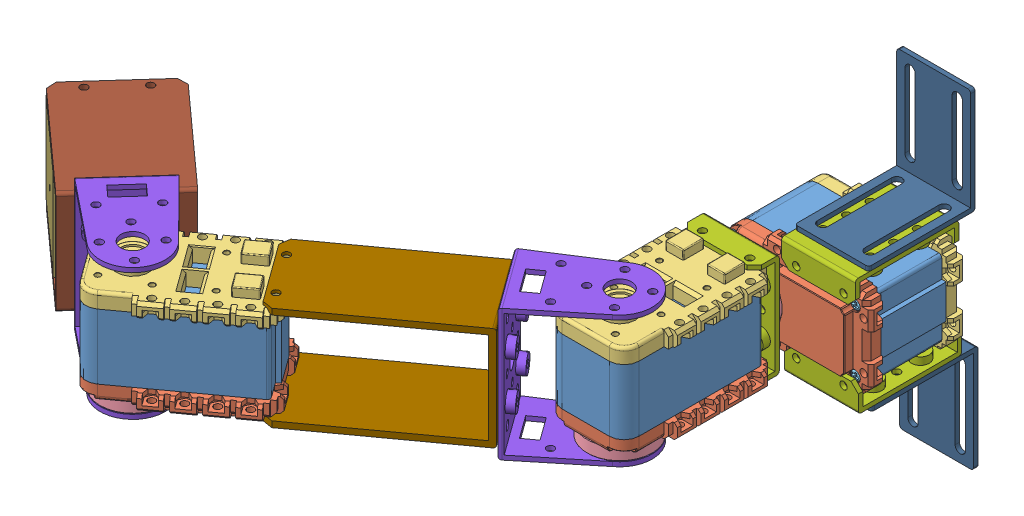
SolidWorks assembly AX-12A, configuration Default. Lengths in mm.
Overall size (199.49 111 175.01).
27 component instances, 12 part files, 97 mates.
Components (placement in the parent):
- AX-12A-01-1: AX-12A-01 [Default] at origin size (48.5 26 22)
- AX-12A-02-1: AX-12A-02 [Default] at (0 0 13.5) size (50 32 8)
- AX-12A-03-1: AX-12A-03 [Default] at (0 0 -13.5) x (1 0 0) z (0 0 -1) size (50 32 8)
- AX-12A-04-1: AX-12A-04 [Default] at (0 0 21) size (22 22 6.7)
- SetScrew-5: SetScrew [Default] at (33 10.4 14.5) x (0.31498 0.949098 0) z (0 0 -1) size (3.3 3.3 29.44)
- SetScrew-6: SetScrew [Default] at (-9 9.25 14.5) x (0.31498 0.949098 0) z (0 0 -1) size (3.3 3.3 29.44)
- SetScrew-7: SetScrew [Default] at (-9 -9.25 14.5) x (-0.839745 -0.542981 0) z (0 0 -1) size (3.3 3.3 29.44)
- SetScrew-8: SetScrew [Default] at (33 -10.4 14.5) x (0.31498 0.949098 0) z (0 0 -1) size (3.3 3.3 29.44)
- pan head cross recess screw_iso-1: pan head cross recess screw_iso [ISO 7045 - M2.5 x 8 - Z --- 8C] at (0 0 21.6) x (0 0 -1) z (0.97903 -0.203716 0) size (10.05 5 5)
- servovas-1: servovas [Default] at (34.75 19.5 -17.5) x (0 0 1) z (0 -1 0) size (35 25 8.5)
- servovas-2: servovas [Default] at (10.75 -19.5 -17.5) x (0 0 1) z (0 1 0) size (35 25 8.5)
- AX-12A-01-2: AX-12A-01 [Default] at (0.5 0 63) x (0 0 -1) z (0 -1 0) size (48.5 26 22)
- AX-12A-02-2: AX-12A-02 [Default] at (0.5 -13.5 63) x (0 0 -1) z (0 -1 0) size (50 32 8)
- AX-12A-03-2: AX-12A-03 [Default] at (0.5 13.5 63) x (0 0 -1) z (0 1 0) size (50 32 8)
- AX-12A-04-2: AX-12A-04 [Default] at (0.5 -20.45 63) x (0.809362 0 -0.587311) z (0 -1 0) size (22 22 6.7)
- servovas-3: servovas [Default] at (12.5 -17.5 21) x (0 1 0) z (0 0 1) size (35 25 8.5)
- connectingpart1-2: connectingpart1 [Default] at (-29.0988 -21.95 69.034) x (0 1 0) z (0.809362 0 -0.587311) size (44.5 25 38.5)
- servovas2.0-1: servovas2.0 [Default] at (-13.2414 -17.2 90.8868) x (0 1 0) z (-0.809362 0 0.587311) size (35 29 57)
- connectingpart2-1: connectingpart2 [Default] at (9.75 19.5 -23) x (0 0 1) z (-1 0 0) size (36 36 25)
- connectingpart2-2: connectingpart2 [Default] at (35.75 -19.5 -23) x (0 0 1) z (1 0 0) size (36 36 25)
- AX-12A-01-4: AX-12A-01 [Default] at (-95.0047 0.8 132.3026) x (0.809362 0 -0.587311) z (0 1 0) size (48.5 26 22)
- AX-12A-02-4: AX-12A-02 [Default] at (-95.0047 -12.7 132.3026) x (0.809362 0 -0.587311) z (0 -1 0) size (50 32 8)
- AX-12A-03-4: AX-12A-03 [Default] at (-95.0047 14.3 132.3026) x (0.809362 0 -0.587311) z (0 1 0) size (50 32 8)
- AX-12A-04-4: AX-12A-04 [Default] at (-95.0047 -19.65 132.3026) x (0.742896 0 0.669406) z (0 -1 0) size (22 22 6.7)
- connectingpart1-3: connectingpart1 [Default] at (-107.0668 -21.15 104.6078) x (0 1 0) z (0.742896 0 0.669406) size (44.5 25 38.5)
- servovas2.1-1: servovas2.1 [Default] at (-104.0544 18.6 101.2647) x (0 -1 0) z (-0.742896 0 -0.669406) size (35 34 46)
- markertarto-1: markertarto [Default] at (-112.2263 -15.4 93.9013) x (-0.669406 0 0.742896) z (0 -1 0) size (34 35 32.01)
Mates (geometry in assembly coordinates):
- Coincident1: coincident: plane of AX-12A-01-1 through (0 0 11) normal (0 0 1); plane of AX-12A-02-1 through (0 0 11) normal (0 0 -1)
- Coincident2: coincident: plane of AX-12A-01-1 through (0 0 0) normal (1 0 0); plane of AX-12A-02-1 through (0 0 13.5) normal (1 0 0)
- Coincident3: coincident: plane of AX-12A-01-1 through (0 0 0) normal (0 1 0); plane of AX-12A-02-1 through (0 0 13.5) normal (0 1 0)
- Coincident4: coincident: plane of AX-12A-01-1 through (0 0 -11) normal (0 0 -1); plane of AX-12A-03-1 through (0 0 -11) normal (0 0 1)
- Coincident5: coincident: plane of AX-12A-01-1 through (0 0 0) normal (1 0 0); plane of AX-12A-03-1 through (0 0 -13.5) normal (1 0 0)
- Coincident6: coincident: plane of AX-12A-01-1 through (0 0 0) normal (0 1 0); plane of AX-12A-03-1 through (0 0 -13.5) normal (0 -1 0)
- Concentric1: concentric: cylinder of AX-12A-02-1 through (0 0 13.75) axis (0 0 1) radius 4.75; cylinder of AX-12A-04-1 through (0 0 21) axis (0 0 -1) radius 4.5
- Distance1: distance = 5 mm: plane of AX-12A-02-1 through (0 0 16) normal (0 0 1); plane of AX-12A-04-1 through (0 2.75 21) normal (0 0 1)
- Coincident7: coincident: plane of AX-12A-04-1 through (0 0 21) normal (1 0 0); plane of assembly through (0 0 0) normal (1 0 0)
- Concentric2: concentric: cylinder of AX-12A-02-1 through (33 10.4 11) axis (0 0 1) radius 1; cylinder of SetScrew-5 through (33 10.4 14.5) axis (0 0 1) radius 0.85
- Coincident8: coincident: plane of AX-12A-02-1 through (0 0 14.5) normal (0 0 1); plane of SetScrew-5 through (33.8067 10.1323 14.5) normal (0 0 -1)
- Concentric3: concentric: cylinder of AX-12A-02-1 through (-9 9.25 11) axis (0 0 1) radius 1; cylinder of SetScrew-6 through (-9 9.25 14.5) axis (0 0 1) radius 0.85
- Coincident9: coincident: plane of AX-12A-02-1 through (0 0 14.5) normal (0 0 1); plane of SetScrew-6 through (-8.1933 8.9823 14.5) normal (0 0 -1)
- Concentric4: concentric: cylinder of AX-12A-02-1 through (-9 -9.25 11) axis (0 0 1) radius 1; cylinder of SetScrew-7 through (-9 -9.25 14.5) axis (0 0 1) radius 0.85
- Coincident10: coincident: plane of AX-12A-02-1 through (0 0 14.5) normal (0 0 1); plane of SetScrew-7 through (-9.4615 -8.5362 14.5) normal (0 0 -1)
- Concentric5: concentric: cylinder of AX-12A-02-1 through (33 -10.4 11) axis (0 0 1) radius 1; cylinder of SetScrew-8 through (33 -10.4 14.5) axis (0 0 1) radius 0.85
- Coincident11: coincident: plane of AX-12A-02-1 through (0 0 14.5) normal (0 0 1); plane of SetScrew-8 through (33.8067 -10.6677 14.5) normal (0 0 -1)
- Concentric71: concentric: cylinder of AX-12A-04-1 through (0 0 21) axis (0 0 -1) radius 2.75; cylinder of pan head cross recess screw_iso-1 through (0 0 47) axis (0 0 1) radius 2.5
- Coincident131: coincident: plane of AX-12A-04-1 through (0 2.75 19.5) normal (0 0 1); plane of pan head cross recess screw_iso-1 through (0.2546 1.2238 19.5) normal (0 0 -1)
- Coincident133: coincident: plane of AX-12A-03-1 through (0 0 -16) normal (0 0 -1); plane of servovas-1 through (9.75 18 -16) normal (0 0 1)
- Concentric75: concentric: circle of AX-12A-03-1; circle of servovas-1
- Concentric76: concentric: circle of AX-12A-03-1; circle of servovas-1
- Coincident136: coincident: plane of AX-12A-02-1 through (0 0 16) normal (0 0 1); plane of servovas-2 through (35.75 -18 16) normal (0 0 -1)
- Coincident139: coincident: cylinder of AX-12A-02-1 through (30.75 -13.5 10.999) axis (0 0 1) radius 1.25; circle of servovas-2
- Concentric79: concentric: circle of AX-12A-02-1; circle of servovas-2
- Concentric81: concentric: circle of AX-12A-01-2; circle of AX-12A-03-2
- Concentric82: concentric: circle of AX-12A-01-2; circle of AX-12A-03-2
- Coincident140: coincident: plane of AX-12A-01-2 through (0.5 11 63) normal (0 1 0); plane of AX-12A-03-2 through (0.5 11 63) normal (0 -1 0)
- Coincident141: coincident: circle of AX-12A-01-2; circle of AX-12A-02-2
- Concentric83: concentric: circle of AX-12A-02-2; circle of AX-12A-04-2
- Coincident143: coincident: circle of AX-12A-01-2; circle of AX-12A-02-2
- Coincident144: coincident: circle of AX-12A-02-2; circle of servovas-3
- Coincident145: coincident: circle of AX-12A-03-2; circle of servovas-3
- Concentric85: concentric: cylinder of AX-12A-02-2 through (0.5 -13.75 63) axis (0 -1 0) radius 4.75; cylinder of AX-12A-04-2 through (0.5 -20.45 63) axis (0 1 0) radius 4.5
- Coincident149: coincident: plane of AX-12A-02-2 through (0.5 -13.75 63) normal (0 -1 0); plane of AX-12A-04-2 through (3.1429 -13.75 66.6421) normal (0 1 0)
- Concentric86: concentric: circle of AX-12A-04-2; circle of connectingpart1-2
- Coincident150: coincident: plane of AX-12A-04-2 through (2.1151 -20.45 65.2257) normal (0 -1 0); plane of connectingpart1-2 through (-13.202 -20.45 88.3871) normal (0 1 0)
- Concentric87: concentric: circle of AX-12A-04-2; circle of connectingpart1-2
- Coincident156: coincident: plane of ? through (114.2121 10.8 139.7397) normal (0 1 0); plane of ? through (114.2121 10.8 139.7397) normal (0 -1 0)
- Concentric90: concentric: circle of ?; circle of ?
- Coincident158: coincident: plane of ? through (114.2121 -11.2 139.7397) normal (0 -1 0); plane of ? through (114.2121 -11.2 139.7397) normal (0 1 0)
- Coincident159: coincident: circle of ?; circle of ?
- Concentric91: concentric: circle of ?; circle of ?
- Coincident162: coincident: circle of ?; circle of ?
- Concentric93: concentric: circle of ?; circle of connectingpart1-3
- Coincident165: coincident: plane of ? through (121.1215 -23.15 85.3294) normal (0 -1 0); plane of connectingpart1-3 through (115.783 -23.15 55.6635) normal (0 1 0)
- Concentric94: concentric: circle of ?; circle of connectingpart1-3
- Concentric95: concentric: circle of ?; circle of ?
- Coincident166: coincident: plane of ? through (114.2121 -16.45 139.7397) normal (0 -1 0); plane of ? through (118.5984 -16.45 140.7451) normal (0 1 0)
- Coincident178: coincident: plane of AX-12A-04-1 through (0 2.75 21) normal (0 0 1); plane of ? through (-12.5 20.25 21) normal (0 0 -1)
- Coincident179: coincident: plane of servovas-3 through (12.5 -17.5 61) normal (0 0 -1); plane of ? through (-12.5 20.25 61) normal (0 0 1)
- Coincident185: coincident: circle of connectingpart1-2; circle of servovas2.0-1
- Coincident186: coincident: circle of connectingpart1-2; circle of servovas2.0-1
- Coincident187: coincident: circle of ?; circle of servovas2.0-1
- Coincident190: coincident: plane of connectingpart1-3; plane of ? through (139.7643 15.1 62.8849) normal (-0.345167 0 0.938541)
- Coincident191: coincident: circle of connectingpart1-3; circle of ?
- Coincident192: coincident: circle of connectingpart1-3; circle of ?
- Coincident193: coincident: plane of AX-12A-01-4 through (-95.0047 11.8 132.3026) normal (0 1 0); plane of AX-12A-03-4 through (-95.0047 11.8 132.3026) normal (0 -1 0)
- Concentric99: concentric: circle of AX-12A-01-4; circle of AX-12A-03-4
- Concentric100: concentric: circle of AX-12A-01-4; circle of AX-12A-03-4
- Coincident194: coincident: plane of AX-12A-01-4 through (-95.0047 -10.2 132.3026) normal (0 -1 0); plane of AX-12A-02-4 through (-95.0047 -10.2 132.3026) normal (0 1 0)
- Coincident195: coincident: circle of AX-12A-01-4; circle of AX-12A-02-4
- Coincident196: coincident: circle of AX-12A-01-4; circle of AX-12A-02-4
- Concentric101: concentric: circle of AX-12A-02-4; circle of AX-12A-04-4
- Coincident197: coincident: plane of AX-12A-02-4 through (-95.0047 -12.95 132.3026) normal (0 -1 0); plane of AX-12A-04-4 through (-98.017 -12.95 135.6457) normal (0 1 0)
- Coincident198: coincident: circle of AX-12A-02-4; circle of ?
- Coincident199: coincident: circle of AX-12A-02-4; circle of ?
- Coincident200: coincident: plane of AX-12A-04-4 through (144.1087 -22.85 21.8402) normal (0 -1 0); plane of ? through (154.0341 -22.85 -23.7974) normal (0 1 0)
- Coincident201: coincident: plane of servovas-1 through (34.75 19.5 -17.5) normal (0 1 0); plane of connectingpart2-1 through (9.75 19.5 -23) normal (0 -1 0)
- Concentric104: concentric: circle of servovas-1; circle of connectingpart2-1
- Concentric105: concentric: circle of servovas-1; circle of connectingpart2-1
- Coincident202: coincident: plane of servovas-2 through (10.75 -19.5 -17.5) normal (0 -1 0); plane of connectingpart2-2 through (35.75 -19.5 -23) normal (0 1 0)
- Concentric106: concentric: circle of servovas-2; circle of connectingpart2-2
- Concentric107: concentric: circle of servovas-2; circle of connectingpart2-2
- Concentric110: concentric: circle of AX-12A-04-4; circle of ?
- Concentric111: concentric: circle of AX-12A-04-4; circle of ?
- Concentric112: concentric: circle of AX-12A-04-1; circle of ?
- Concentric114: concentric: circle of AX-12A-04-1; circle of ?
- Coincident203: coincident: circle of servovas-3; circle of ?
- Concentric115: concentric: circle of servovas-3; circle of ?
- Coincident204: coincident: circle of ?; circle of servovas2.0-1
- Coincident206: coincident: plane of ? through (116.8926 -23.15 140.3541) normal (0 -1 0); plane of ? through (148.8368 -23.15 111.7686) normal (0 1 0)
- Concentric116: concentric: circle of ?; circle of ?
- Concentric119: concentric: circle of ?; circle of ?
- Concentric120: concentric: circle of AX-12A-04-1; circle of servovas-3
- Concentric121: concentric: circle of AX-12A-04-1; circle of servovas-3
- Coincident207: coincident: plane of AX-12A-04-1 through (0 2.75 21) normal (0 0 1); plane of servovas-3 through (12.5 -17.5 21) normal (0 0 -1)
- Coincident209: coincident: circle of servovas2.0-1; circle of AX-12A-02-4
- Concentric123: concentric: circle of servovas2.0-1; circle of AX-12A-03-4
- Coincident211: coincident: plane of AX-12A-04-4 through (-96.8455 -19.65 134.3456) normal (0 -1 0); plane of connectingpart1-3 through (-122.6876 -19.65 124.1843) normal (0 1 0)
- Concentric125: concentric: circle of AX-12A-04-4; circle of connectingpart1-3
- Concentric126: concentric: circle of AX-12A-04-4; circle of connectingpart1-3
- Coincident215: coincident: plane of connectingpart1-3 through (-107.0668 -21.15 104.6078) normal (-0.742896 0 -0.669406); plane of servovas2.1-1 through (-104.0544 18.6 101.2647) normal (0.742896 0 0.669406)
- Coincident216: coincident: circle of servovas2.1-1; circle of markertarto-1
- Concentric129: concentric: circle of servovas2.1-1; circle of markertarto-1
- Coincident217: coincident: circle of connectingpart1-3; circle of servovas2.1-1
- Concentric130: concentric: circle of connectingpart1-3; circle of servovas2.1-1
